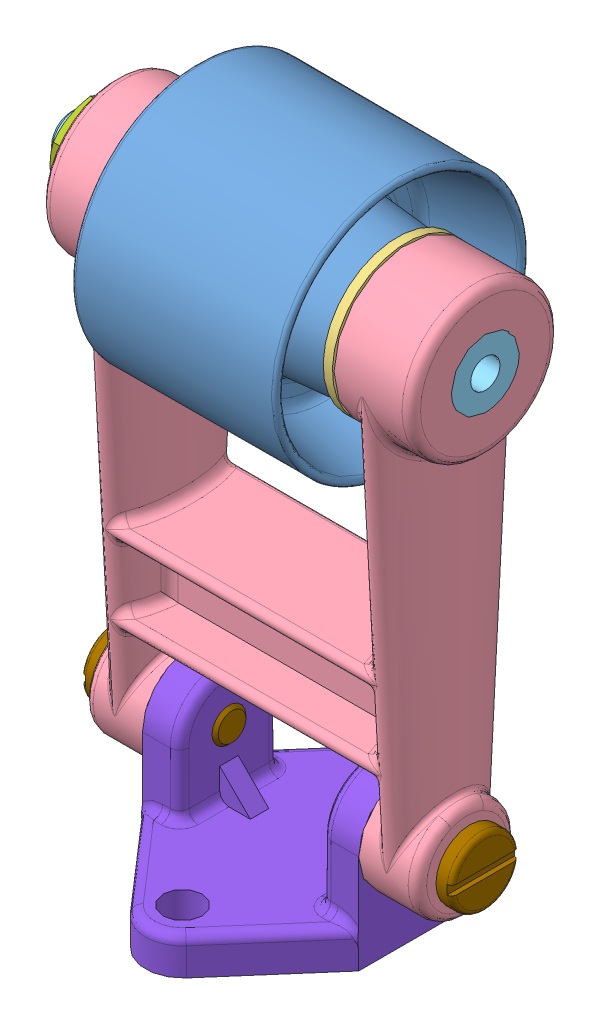
SolidWorks assembly ASSEMBLY v2 RIB, configuration Default. Lengths in mm.
Overall size (134.09 213.84 100).
11 component instances, 9 part files, 23 mates.
Components (placement in the parent):
- PULLEY v2-1: PULLEY v2 [Default] at origin size (68.15 83.68 83.68)
- BUSHING v2-1: BUSHING v2 [Default] at origin size (63 26.9 26.9)
- WASHER v1-1: WASHER v1 [Default] at (31.5 0 0) x (0 0.448797 -0.893634) z (-1 0 0) size (48 48 3)
- WASHER v1-2: WASHER v1 [Default] at (-34.5 0 0) x (0 0.448797 -0.893634) z (-1 0 0) size (48 48 3)
- Frame_final-1: Frame_final [Default] at (0 -140 0) size (120 180 51.83)
- SHAFT-1: SHAFT [Default] at (-7 0 0) size (134 22 22)
- WOODRUFF KEY #406-1: WOODRUFF KEY #406 [Default] at (-46 11.1125 0) size (18.79 7.95 3.17)
- HEX NUT V1-2: HEX NUT V1 [Default] at (-69 0 0) x (-1 0 0) z (0 0 1) size (9 27.71 24)
- BRACKET v2 RIB-1: BRACKET v2 RIB [Default] at (0 -172 0) x (0 0 -1) z (1 0 0) size (100 48 70.6)
- PIN v2-1: PIN v2 [Default] at (-60 -140 0) size (38.09 22 22)
- PIN v2-2: PIN v2 [Default] at (60 -140 0) x (-1 0 0) z (0 0 -1) size (38.09 22 22)
Mates (geometry in assembly coordinates):
- Concentric1: concentric aligned: cylinder of PULLEY v2-1 through (-113.6273 0 0) axis (-1 0 0) radius 13.45; cylinder of BUSHING v2-1 through (-66.3727 0 0) axis (-1 0 0) radius 13.45
- Coincident1: coincident aligned: plane of PULLEY v2-1 through (31.5 22 0) normal (1 0 0); plane of BUSHING v2-1 through (31.5 13.45 0) normal (1 0 0)
- Coincident2: coincident aligned: plane of BUSHING v2-1 through (0 0 0) normal (0 0 1); plane of assembly through (0 0 0) normal (0 0 1)
- Concentric4: concentric aligned: cylinder of BUSHING v2-1 through (-66.3727 0 0) axis (-1 0 0) radius 9.6216; cylinder of WASHER v1-1 through (34.501 0 0) axis (-1 0 0) radius 9.5
- Coincident4: coincident anti-aligned: plane of BUSHING v2-1 through (31.5 13.45 0) normal (1 0 0); plane of WASHER v1-1 through (31.5 0 0) normal (-1 0 0)
- Concentric5: concentric anti-aligned: cylinder of BUSHING v2-1 through (-66.3727 0 0) axis (-1 0 0) radius 9.6216; cylinder of Frame_final-1 through (-60.001 0 0) axis (1 0 0) radius 11
- Distance1: distance = 35 mm aligned: plane of Frame_final-1 through (-35 0 0) normal (1 0 0); plane of assembly through (0 0 0) normal (1 0 0)
- Coincident6: coincident aligned: plane of Frame_final-1 through (0 -140 0) normal (0 0 1); plane of assembly through (0 0 0) normal (0 0 1)
- Concentric6: concentric anti-aligned: cylinder of SHAFT-1 through (-46 11.1125 -1.5875) axis (0 0 1) radius 9.525; cylinder of WOODRUFF KEY #406-1 through (-46 11.1125 1.5875) axis (0 0 -1) radius 9.525
- Coincident7: coincident aligned: plane of SHAFT-1 through (-7 0 0) normal (0 0 1); plane of WOODRUFF KEY #406-1 through (-46 11.1125 0) normal (0 0 1)
- Concentric7: concentric anti-aligned: cylinder of Frame_final-1 through (-60.001 0 0) axis (1 0 0) radius 11; cylinder of SHAFT-1 through (-91.9355 0 0) axis (-1 0 0) radius 11
- Coincident8: coincident aligned: plane of Frame_final-1 through (60 0 0) normal (1 0 0); plane of SHAFT-1 through (60 0 0) normal (1 0 0)
- Parallel2: parallel aligned: plane of SHAFT-1 through (-7 0 0) normal (0 1 0); plane of WOODRUFF KEY #406-1 through (-46 11.1125 0) normal (0 1 0)
- Coincident10: coincident aligned: plane of SHAFT-1 through (-7 0 0) normal (0 0 1); plane of assembly through (0 0 0) normal (0 0 1)
- Concentric8: concentric aligned: cylinder of Frame_final-1 through (60.001 0 0) axis (-1 0 0) radius 8; cylinder of HEX NUT V1-2 through (-69 0 0) axis (-1 0 0) radius 7
- Coincident11: coincident anti-aligned: plane of Frame_final-1 through (-60 0 0) normal (-1 0 0); plane of HEX NUT V1-2 through (-60 0 0) normal (1 0 0)
- Coincident14: coincident aligned: plane of HEX NUT V1-2 through (-69 0 0) normal (0 0 1); plane of assembly through (0 0 0) normal (0 0 1)
- Concentric9: concentric anti-aligned: cylinder of Frame_final-1 through (54 -140 0) axis (-1 0 0) radius 8; cylinder of BRACKET v2 RIB-1 through (35 -140 0) axis (1 0 0) radius 5.1
- Coincident15: coincident anti-aligned: plane of Frame_final-1 through (35 -140 0) normal (-1 0 0); plane of BRACKET v2 RIB-1 through (35 -160 16) normal (1 0 0)
- Coincident17: coincident anti-aligned: plane of BRACKET v2 RIB-1 through (0 -172 0) normal (0 0 -1); plane of assembly through (0 0 0) normal (0 0 1)
- Concentric10: concentric aligned: cylinder of BRACKET v2 RIB-1 through (-35 -140 0) axis (-1 0 0) radius 5.1; cylinder of PIN v2-1 through (-157.3189 -140 0) axis (-1 0 0) radius 6
- Coincident18: coincident anti-aligned: plane of BRACKET v2 RIB-1 through (-35 -160 16) normal (-1 0 0); plane of PIN v2-1 through (-35 -132 0) normal (1 0 0)
- Perpendicular1: perpendicular: plane of PIN v2-1 through (-60 -140 0) normal (0 1 0); plane of assembly through (0 0 0) normal (0 0 1)
